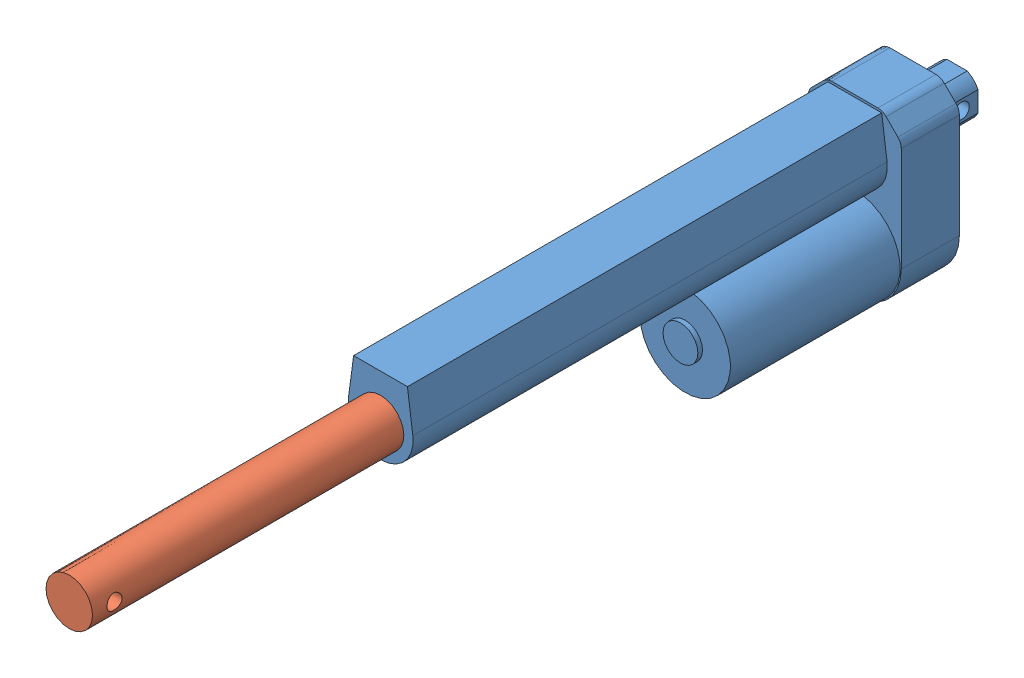
SolidWorks assembly 150mm行程直线电机, configuration 默认. Lengths in mm.
2 component instances, 2 part files, 3 mates.
Components (placement in the parent):
- 直线电机外壳_200mm-1: 直线电机外壳_200mm [默认] at (-20.3863 -14.9121 143) size (40 75 248)
- 直线电机轴_短-1: 直线电机轴_短 [默认] at (-20.3863 20.0879 505.9138) x (0 1 0) z (0 0 -1) size (20 20 190)
Mates (geometry in assembly coordinates):
- 同心1: concentric: cylinder of 直线电机外壳_200mm-1 through (-20.3863 20.0879 -38) axis (0 0 1) radius 10; cylinder of 直线电机轴_短-1 through (-20.3863 20.0879 315.9138) axis (0 0 1) radius 10
- LimitDistance1: limit distance = 358.9138 mm: cylinder of 直线电机轴_短-1 through (-230.3863 20.0879 496.4138) axis (1 0 0) radius 3.25; cylinder of 直线电机外壳_200mm-1 through (-31.3863 20.0879 131) axis (1 0 0) radius 3.25
- 平行1: parallel: cylinder of 直线电机外壳_200mm-1 through (-31.3863 20.0879 131) axis (1 0 0) radius 3.25; cylinder of 直线电机轴_短-1 through (-230.3863 20.0879 496.4138) axis (1 0 0) radius 3.25
